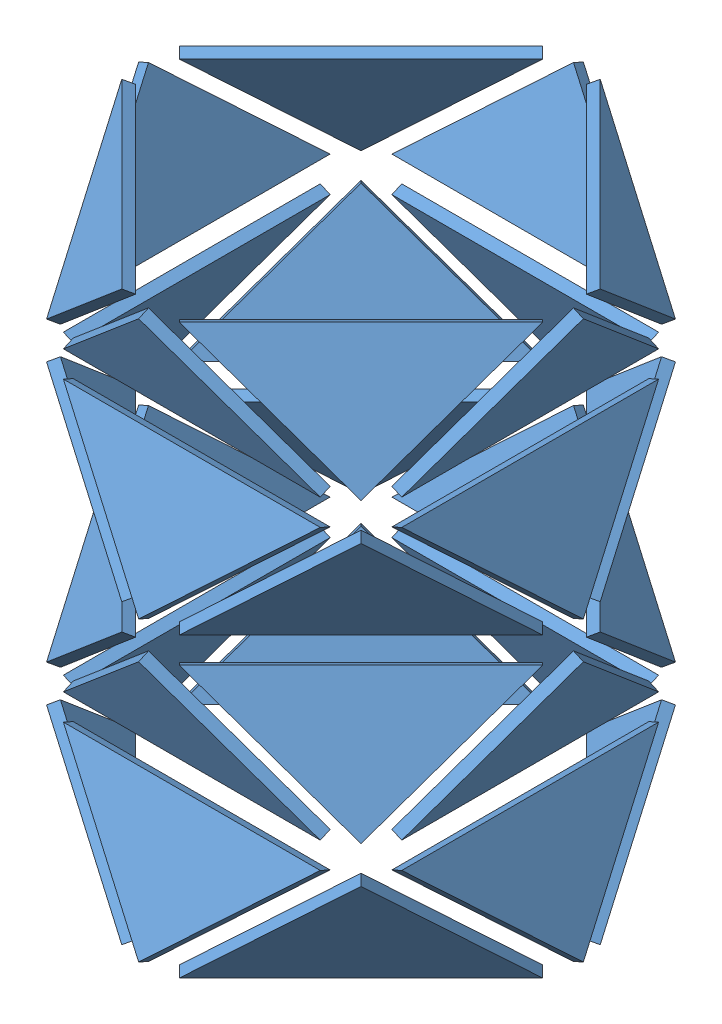
SolidWorks assembly Assem2, configuration Default. Lengths in mm.
Overall size (128.31 247.75 128.31).
32 component instances, 1 part files, 7 mates.
Components (placement in the parent):
- right triangle-1: right triangle [Default] at (0 36.1422 61.8137) x (0.707107 -0.643594 -0.292893) z (0.707107 0.643594 0.292893) size (64.16 3 64.16)
- right triangle-2: right triangle [Default] at (43.7089 5.1488 43.7089) x (-0.707107 0.643594 0.292893) z (-0.292893 -0.643594 0.707107) size (64.16 3 64.16)
- right triangle-3: right triangle [Default] at (0 -37.3849 59.0832) x (0.707107 0.643594 -0.292893) z (0.707107 -0.643594 0.292893) size (64.16 3 64.16)
- right triangle-4: right triangle [Default] at (41.7781 -3.9061 41.7781) x (-0.707107 -0.643594 0.292893) z (-0.292893 0.643594 0.707107) size (64.16 3 64.16)
- right triangle-5: right triangle [Default] at (-59.0832 -37.3849 0) x (0.292893 0.643594 0.707107) z (-0.292893 -0.643594 0.707107) size (64.16 3 64.16)
- right triangle-6: right triangle [Default] at (0 -37.3849 -59.0832) x (-0.707107 0.643594 0.292893) z (-0.707107 -0.643594 -0.292893) size (64.16 3 64.16)
- right triangle-7: right triangle [Default] at (59.0832 -37.3849 0) x (-0.292893 0.643594 -0.707107) z (0.292893 -0.643594 -0.707107) size (64.16 3 64.16)
- right triangle-8: right triangle [Default] at (-41.7781 -3.9061 41.7781) x (-0.292893 -0.643594 -0.707107) z (-0.707107 0.643594 -0.292893) size (64.16 3 64.16)
- right triangle-9: right triangle [Default] at (-41.7781 -3.9061 -41.7781) x (0.707107 -0.643594 -0.292893) z (0.292893 0.643594 -0.707107) size (64.16 3 64.16)
- right triangle-10: right triangle [Default] at (41.7781 -3.9061 -41.7781) x (0.292893 -0.643594 0.707107) z (0.707107 0.643594 0.292893) size (64.16 3 64.16)
- right triangle-11: right triangle [Default] at (-43.7089 5.1488 43.7089) x (-0.292893 0.643594 -0.707107) z (-0.707107 -0.643594 -0.292893) size (64.16 3 64.16)
- right triangle-12: right triangle [Default] at (-43.7089 5.1488 -43.7089) x (0.707107 0.643594 -0.292893) z (0.292893 -0.643594 -0.707107) size (64.16 3 64.16)
- right triangle-13: right triangle [Default] at (43.7089 5.1488 -43.7089) x (0.292893 0.643594 0.707107) z (0.707107 -0.643594 0.292893) size (64.16 3 64.16)
- right triangle-14: right triangle [Default] at (-61.8137 36.1422 0) x (0.292893 -0.643594 0.707107) z (-0.292893 0.643594 0.707107) size (64.16 3 64.16)
- right triangle-15: right triangle [Default] at (0 36.1422 -61.8137) x (-0.707107 -0.643594 0.292893) z (-0.707107 0.643594 -0.292893) size (64.16 3 64.16)
- right triangle-16: right triangle [Default] at (61.8137 36.1422 0) x (-0.292893 -0.643594 -0.707107) z (0.292893 0.643594 -0.707107) size (64.16 3 64.16)
- right triangle-17: right triangle [Default] at (0 45.1971 59.0832) x (0.707107 0.643594 -0.292893) z (0.707107 -0.643594 0.292893) size (64.16 3 64.16)
- right triangle-18: right triangle [Default] at (41.7781 78.6759 41.7781) x (-0.707107 -0.643594 0.292893) z (-0.292893 0.643594 0.707107) size (64.16 3 64.16)
- right triangle-19: right triangle [Default] at (0 118.7242 61.8137) x (0.707107 -0.643594 -0.292893) z (0.707107 0.643594 0.292893) size (64.16 3 64.16)
- right triangle-20: right triangle [Default] at (43.7089 87.7307 43.7089) x (-0.707107 0.643594 0.292893) z (-0.292893 -0.643594 0.707107) size (64.16 3 64.16)
- right triangle-21: right triangle [Default] at (-61.8137 118.7242 0) x (0.292893 -0.643594 0.707107) z (-0.292893 0.643594 0.707107) size (64.16 3 64.16)
- right triangle-22: right triangle [Default] at (0 118.7242 -61.8137) x (-0.707107 -0.643594 0.292893) z (-0.707107 0.643594 -0.292893) size (64.16 3 64.16)
- right triangle-23: right triangle [Default] at (61.8137 118.7242 0) x (-0.292893 -0.643594 -0.707107) z (0.292893 0.643594 -0.707107) size (64.16 3 64.16)
- right triangle-24: right triangle [Default] at (-43.7089 87.7307 43.7089) x (-0.292893 0.643594 -0.707107) z (-0.707107 -0.643594 -0.292893) size (64.16 3 64.16)
- right triangle-25: right triangle [Default] at (-43.7089 87.7307 -43.7089) x (0.707107 0.643594 -0.292893) z (0.292893 -0.643594 -0.707107) size (64.16 3 64.16)
- right triangle-26: right triangle [Default] at (43.7089 87.7307 -43.7089) x (0.292893 0.643594 0.707107) z (0.707107 -0.643594 0.292893) size (64.16 3 64.16)
- right triangle-27: right triangle [Default] at (-41.7781 78.6759 41.7781) x (-0.292893 -0.643594 -0.707107) z (-0.707107 0.643594 -0.292893) size (64.16 3 64.16)
- right triangle-28: right triangle [Default] at (-41.7781 78.6759 -41.7781) x (0.707107 -0.643594 -0.292893) z (0.292893 0.643594 -0.707107) size (64.16 3 64.16)
- right triangle-29: right triangle [Default] at (41.7781 78.6759 -41.7781) x (0.292893 -0.643594 0.707107) z (0.707107 0.643594 0.292893) size (64.16 3 64.16)
- right triangle-30: right triangle [Default] at (-59.0832 45.1971 0) x (0.292893 0.643594 0.707107) z (-0.292893 -0.643594 0.707107) size (64.16 3 64.16)
- right triangle-31: right triangle [Default] at (0 45.1971 -59.0832) x (-0.707107 0.643594 0.292893) z (-0.707107 -0.643594 -0.292893) size (64.16 3 64.16)
- right triangle-32: right triangle [Default] at (59.0832 45.1971 0) x (-0.292893 0.643594 -0.707107) z (0.292893 -0.643594 -0.707107) size (64.16 3 64.16)
Mates (geometry in assembly coordinates):
- Coincident1: coincident: line of right triangle-1 through (45.3657 0 45.3657) axis (-1 0 0)
- Coincident2: coincident: unknown of right triangle-1
- Parallel1: parallel: line of right triangle-1 through (45.3657 0 45.3657) axis (-1 0 0)
- Coincident4: coincident anti-aligned: line of right triangle-1 through (45.3657 0 45.3657) axis (-1 0 0)
- Coincident5: coincident: point of right triangle-2; point of assembly
- Coincident6: coincident anti-aligned: line of right triangle-1 through (0 41.291 64.1569) axis (0.707107 -0.643594 -0.292893); line of right triangle-2 through (45.3657 0 45.3657) axis (-0.707107 0.643594 0.292893)
- Coincident7: coincident anti-aligned: plane of right triangle-2 through (43.7089 5.1488 43.7089) normal (0.707107 0 -0.707107)
